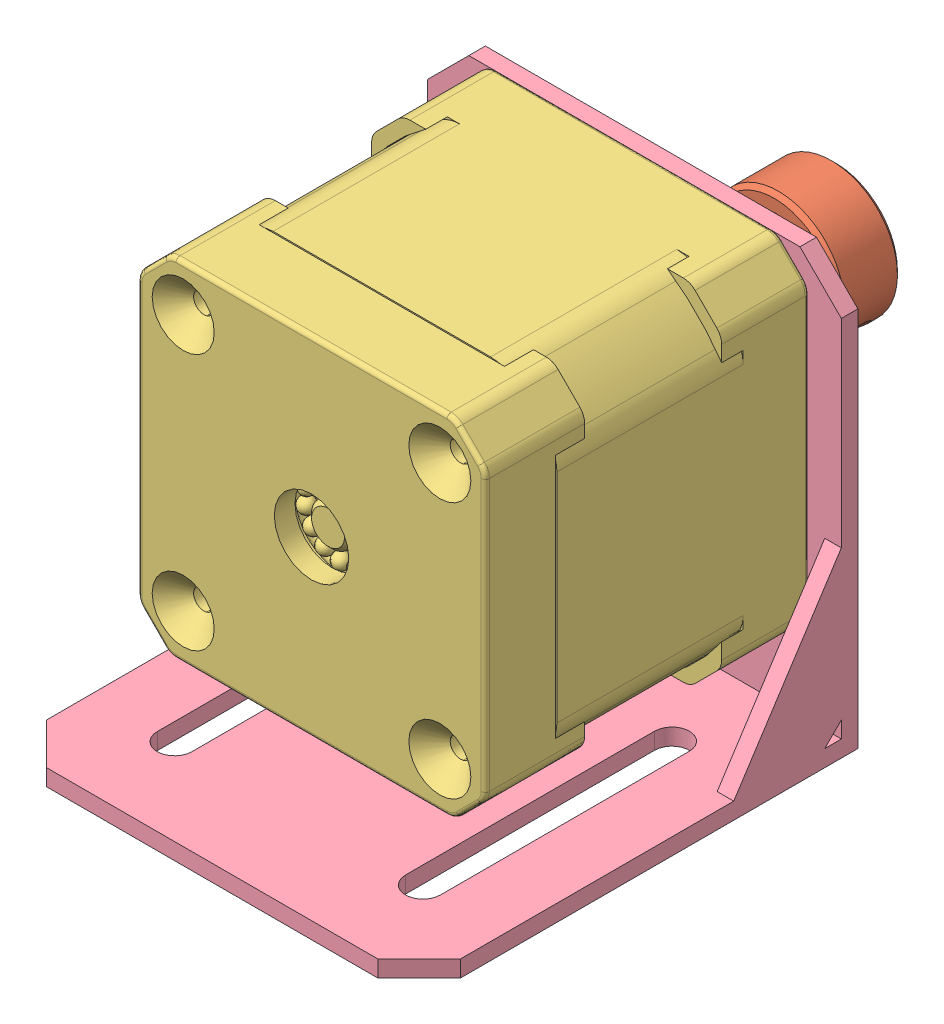
SolidWorks assembly Stepper Motor Assembly, configuration Default. Lengths in mm.
Overall size (50 51.29 75.3).
7 component instances, 5 part files, 14 mates.
Components (placement in the parent):
- Screw-1: Screw [Default] at (147.7106 140.4303 199.9369) x (-0.047434 -0.998874 0) z (0.998874 -0.047434 0) size (7 25.04 7)
- GT2_Pulley20_Teeth.stp-1: GT2_Pulley20_Teeth.stp [Default] at (132.2106 125.0707 168.6369) x (-0.679392 0.733775 0) z (0 0 -1) size (16 16 16)
- NEMA_17_Stepper_Motor.step-1: NEMA_17_Stepper_Motor.step [Default] at (136.9106 140.0707 -883.0631) size (42.3 42.3 63.3)
- Nema17_Mounting_Bracket-1: Nema17_Mounting_Bracket [Default] at (157.2106 94.9303 174.9369) x (0 0 1) z (-1 0 0) size (53 51 50)
- Screw-2: Screw [Default] at (116.7106 109.4303 199.8369) x (1 0 0) z (0 1 0) size (7 25.04 7)
- Screw.step-2: Screw.step [Default] at (147.7106 109.4303 199.9369) x (1 0 0) z (0 1 0) size (7 25.04 7)
- Screw.step-3: Screw.step [Default] at (116.7106 140.5707 199.9369) x (-1 0 0) z (0 -1 0) size (7 25.04 7)
Mates (geometry in assembly coordinates):
- Coincident3: coincident anti-aligned: plane of NEMA_17_Stepper_Motor.step-1 through (132.2106 125.0707 176.9369) normal (0 0 -1); plane of Nema17_Mounting_Bracket-1 through (107.2106 145.9303 176.9369) normal (0 0 1)
- Parallel3: parallel aligned: plane of NEMA_17_Stepper_Motor.step-1 through (111.0606 125.0707 163.9369) normal (-1 0 0); plane of Nema17_Mounting_Bracket-1 through (107.2106 94.9303 174.9369) normal (-1 0 0)
- Concentric7: concentric aligned: circle of NEMA_17_Stepper_Motor.step-1; circle of Nema17_Mounting_Bracket-1
- Coincident9: coincident aligned: plane of Screw-1 through (147.7106 140.4303 174.9369) normal (0 0 -1); plane of Nema17_Mounting_Bracket-1 through (107.2106 94.9303 174.9369) normal (0 0 -1)
- Parallel8: parallel aligned: plane of Nema17_Mounting_Bracket-1 through (107.2106 94.9303 174.9369) normal (0 0 -1); plane of Screw.step-3 through (116.7106 140.5707 174.9369) normal (0 0 -1)
- Concentric15: concentric aligned: cylinder of Nema17_Mounting_Bracket-1 through (116.7106 140.5707 174.9369) axis (0 0 1) radius 2; cone of Screw.step-3 through (116.7106 140.5707 177.7369) axis (0 0 1)
- Tangent14: tangent aligned: plane of Nema17_Mounting_Bracket-1 through (107.2106 94.9303 174.9369) normal (0 0 -1); torus of Screw.step-3
- Concentric16: concentric aligned: cylinder of Nema17_Mounting_Bracket-1 through (116.7106 109.4303 174.9369) axis (0 0 1) radius 2; cone of Screw-2 through (116.7106 109.4303 177.6369) axis (0 0 1)
- Concentric17: concentric aligned: cylinder of Nema17_Mounting_Bracket-1 through (147.7106 109.4303 174.9369) axis (0 0 1) radius 2; cone of Screw.step-2 through (147.7106 109.4303 177.7369) axis (0 0 1)
- Coincident13: coincident anti-aligned: plane of Nema17_Mounting_Bracket-1 through (107.2106 94.9303 174.9369) normal (0 0 -1); circle of Screw-2
- Tangent15: tangent aligned: plane of Nema17_Mounting_Bracket-1 through (107.2106 94.9303 174.9369) normal (0 0 -1); torus of Screw.step-2
- Concentric21: concentric aligned: cone of Screw-1 through (147.7106 140.4303 177.7369) axis (0 0 1); cylinder of Nema17_Mounting_Bracket-1 through (147.7106 140.4303 174.9369) axis (0 0 1) radius 2
- Coincident14: coincident aligned: plane of GT2_Pulley20_Teeth.stp-1 through (137.6287 119.2188 152.6369) normal (0 0 -1); plane of NEMA_17_Stepper_Motor.step-1 through (132.2106 125.0707 152.6369) normal (0 0 -1)
- Concentric24: concentric anti-aligned: cylinder of GT2_Pulley20_Teeth.stp-1 through (132.2106 125.0707 160.6369) axis (0 0 1) radius 2.5; cylinder of NEMA_17_Stepper_Motor.step-1 through (132.2106 125.0707 174.9369) axis (0 0 -1) radius 2.5
